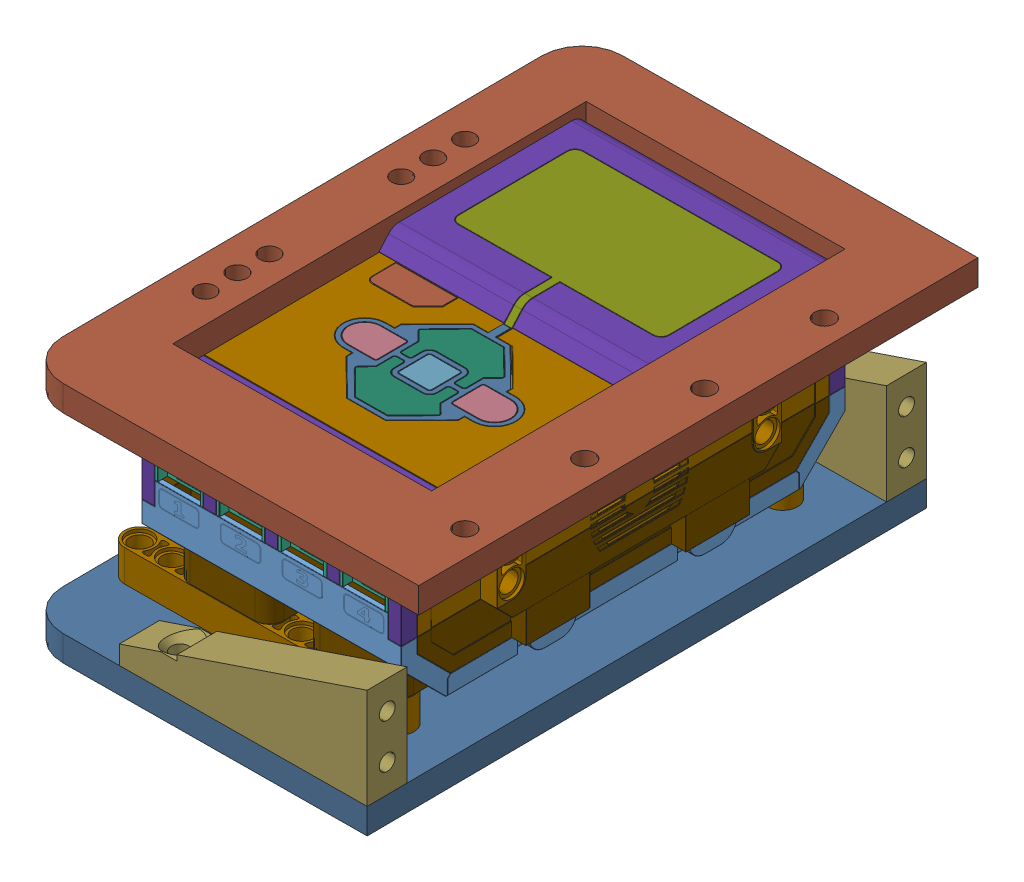
SolidWorks assembly EV3MountAssem, configuration Default. Lengths in mm.
Overall size (98.77 60.15 140.75).
51 component instances, 30 part files, 34 mates.
Components (placement in the parent):
- LEGOEV3BRAIN-1: LEGOEV3BRAIN [Default] at (-108.1242 39.401 63.9633) x (0.99997 0 -0.007691) z (0.007691 0 0.99997) size (72.13 50.8 111.2)
  - 95646c01.stp-1: 95646c01.stp [Default] at origin size (72.13 50.8 111.2)
    - 95656.stp-1: 95656.stp [Default] at (0 -35.2 -16) size (68.8 24 88.8)
      - 11142-LtBluishGray.stp-1: 11142-LtBluishGray.stp [Default] at origin size (68.8 20.8 88.8)
      - 11143-LtBluishGray.stp-1: 11143-LtBluishGray.stp [Default] at (-0.4 -0.4 0) size (50 15.2 87.61)
      - 56554-ElectricAlloy.stp-1: 56554-ElectricAlloy.stp [Default] at (-22.8 4.4 -36) x (0 1 0) z (0 0 1) size (5.6 5.52 5.6)
      - 56555-ElectricAlloy.stp-1: 56555-ElectricAlloy.stp [Default] at (-20.8 4.4 36.4) x (0 0 -1) z (-1 0 0) size (9.6 8.8 0.8)
      - 11177-TransGeen.stp-1: 11177-TransGeen.stp [Default] at (9.6 -8 41.6) x (1 0 0) z (0 -1 0) size (3.2 5.6 3.2)
      - 11177-TransRed.stp-1: 11177-TransRed.stp [Default] at (14.8 -8 41.6) x (1 0 0) z (0 -1 0) size (3.2 5.6 3.2)
      - 11186-Black.stp-1: 11186-Black.stp [Default] at (0 0.8 40) x (0 1 0) z (1 0 0) size (7.2 7.2 4.8)
      - u9208.stp-1: u9208.stp [Default] at (21.6 4.4 36.8) x (1 0 0) z (0 0 -1) size (3.2 8.8 3.2)
      - u9208.stp-2: u9208.stp [Default] at (21.6 4.4 -40) x (1 0 0) z (0 0 -1) size (3.2 8.8 3.2)
      - u9208.stp-3: u9208.stp [Default] at (21.6 4.4 0) x (1 0 0) z (0 0 -1) size (3.2 8.8 3.2)
      - u9208.stp-4: u9208.stp [Default] at (-20.8 4.4 28) x (1 0 0) z (0 0 -1) size (3.2 8.8 3.2)
      - u9208.stp-5: u9208.stp [Default] at (-20.8 4.4 -27.6) x (1 0 0) z (0 0 -1) size (3.2 8.8 3.2)
    - 99141p01-White.stp-1: 99141p01-White.stp [Default] at origin size (72.13 26.01 104.41)
    - 11026-TransClear.stp-1: 11026-TransClear.stp [Default] at (0 -2.6 0) size (42.56 5.2 35.4)
    - 11030-LtBluishGray.stp-1: 11030-LtBluishGray.stp [Default] at (-20 -2.5473 -15.88) size (15.28 5.2 7.44)
    - 11036-LCD.stp-1: 11036-LCD.stp [Default] at (0 1.999 -45.7343) size (52 1.6 40)
    - 99145-LtBluishGray.stp-1: 99145-LtBluishGray.stp [Default] at (-16 -2.6 0) size (10.88 5.2 8.16)
    - 99145-LtBluishGray.stp-2: 99145-LtBluishGray.stp [Default] at (16 -2.6 0) x (-1 0 0) z (0 0 -1) size (10.88 5.2 8.16)
    - 99146-LtBluishGray.stp-1: 99146-LtBluishGray.stp [Default] at (0 -2.6 0) size (8.16 5.2 8.16)
    - 99147-LtBluishGray.stp-1: 99147-LtBluishGray.stp [Default] at (0 -2.6 7.98) x (-1 0 0) z (0 0 -1) size (20.74 5.2 14)
    - 99147-LtBluishGray.stp-2: 99147-LtBluishGray.stp [Default] at (0 -2.6 -7.98) size (20.74 5.2 14)
    - 99148p01-TransClear.stp-1: 99148p01-TransClear.stp [Default] at (0 2.8 -47.2) size (52 8 43.2)
    - 99141s01-LtBluishGray.stp-1: 99141s01-LtBluishGray.stp [Default] at (0 0 2.2) size (64 27.2 111.2)
    - 11025-White.stp-1: 11025-White.stp [Default] at (0 -26.8 -16) size (71.6 22 103.2)
    - 11025s02-LtBluishGray.stp-1: 11025s02-LtBluishGray.stp [Default] at (0 -23.2 -16) size (64 22 111.2)
    - 11032-Black.stp-1: 11032-Black.stp [Default] at (-27.6 -14.6 -32) x (0 0 1) z (-1 0 0) size (14.4 6 14.4)
    - 11033-Black.stp-1: 11033-Black.stp [Default] at (23.2 -15.6 -68.8) x (-1 0 0) z (0 0 -1) size (8.2 4.2 10)
    - 11034-Black.stp-1: 11034-Black.stp [Default] at (-34.8 -16.6 -12) x (0 0 1) z (-1 0 0) size (14.4 2 15.2)
    - 11035-LtBluishGray.stp-1: 11035-LtBluishGray.stp [Default] at (-6 -10.8 -71.6) x (-1 0 0) z (0 0 -1) size (45.6 14.56 14.4)
    - 54732b-LtBluishGray.stp-1: 54732b-LtBluishGray.stp [Default] at (-22.8 -10.8 39.6) size (12 14.56 14.4)
    - 54732b-LtBluishGray.stp-2: 54732b-LtBluishGray.stp [Default] at (-7.6 -10.8 39.6) size (12 14.56 14.4)
    - 54732b-LtBluishGray.stp-3: 54732b-LtBluishGray.stp [Default] at (7.6 -10.8 39.6) size (12 14.56 14.4)
    - 54732b-LtBluishGray.stp-4: 54732b-LtBluishGray.stp [Default] at (22.8 -10.8 39.6) size (12 14.56 14.4)
    - 97622-PCB.stp-1: 97622-PCB.stp [Default] at (0 -6 0) size (48 1.6 40)
- 067_Pin-1: 067_Pin [Pin Without Friction Ridges Lengthwise] at (-115.8778 -0.199 96.0239) x (0 -1 0) z (0.00723 0 0.999974) size (15.6 5.8 5.8)
- 067_Pin-2: 067_Pin [Pin Without Friction Ridges Lengthwise] at (-84.6171 -0.199 -0.2194) x (0 -1 0) z (0.00662 0 0.999978) size (15.6 5.8 5.8)
- 067_Pin-3: 067_Pin [Pin Without Friction Ridges Lengthwise] at (-100.6166 -0.199 -0.0963) x (0 -1 0) z (-0.01457 0 0.999894) size (15.6 5.8 5.8)
- 067_Pin-4: 067_Pin [Pin Without Friction Ridges Lengthwise] at (-99.8783 -0.199 95.9009) x (0 1 0) z (0.010456 0 0.999945) size (15.6 5.8 5.8)
- 067_Pin-5: 067_Pin [Pin Without Friction Ridges Lengthwise] at (-83.8788 -0.199 95.7778) x (0 -1 0) z (0.00723 0 0.999974) size (15.6 5.8 5.8)
- 067_Pin-6: 067_Pin [Pin Without Friction Ridges Lengthwise] at (-131.8773 -0.199 96.147) x (0 -1 0) z (0.027134 0 0.999632) size (15.6 5.8 5.8)
- 067_Pin-7: 067_Pin [Pin Without Friction Ridges Lengthwise] at (-132.6157 -0.199 0.1498) x (0 -1 0) z (-0.015279 0 0.999883) size (15.6 5.8 5.8)
- 067_Pin-8: 067_Pin [Pin Without Friction Ridges Lengthwise] at (-116.6161 -0.199 0.0267) x (0 -1 0) z (0.00723 0 0.999974) size (15.6 5.8 5.8)
- 066_Lego_Technic_M_Beams-1: 066_Lego_Technic_M_Beams [L40490] at (-147.8769 -4.124 96.27) x (0.99997 0 -0.007691) z (0 -1 0) size (71.4 7.4 7.85)
- 066_Lego_Technic_M_Beams-2: 066_Lego_Technic_M_Beams [L40490] at (-148.6152 -4.124 0.2729) x (0.99997 0 -0.007691) z (0 -1 0) size (71.4 7.4 7.85)
- 069_EV3-6: 069_EV3 [Default] at (46.3426 -14.399 -58.7978) x (0.99997 0 -0.007691) z (0.007691 0 0.99997) size (85 6.35 140)
- 070_Top-1: 070_Top [Default] at (-110.5302 39.401 55.873) x (0.99997 0 -0.007691) z (0.007691 0 0.99997) size (97.7 6.35 140)
- 071_Support-1: 071_Support [Default] at (-112.3869 -8.049 107.9974) x (0.007691 0 0.99997) z (-0.99997 0 0.007691) size (10 25 61.12)
- 071_Support-2: 071_Support [Default] at (-113.3867 -8.049 -21.9987) x (0.007691 0 0.99997) z (-0.99997 0 0.007691) size (10 25 61.12)
Mates (geometry in assembly coordinates):
- Concentric1: concentric anti-aligned: cylinder of LEGOEV3BRAIN-1/95646c01.stp-1/11025-White.stp-1 through (-99.8783 -0.199 95.9009) axis (0 1 0) radius 2.4; cylinder of 067_Pin-4 through (-99.8783 -0.199 95.9009) axis (0 -1 0) radius 2.3
- Coincident2: coincident anti-aligned: plane of LEGOEV3BRAIN-1/95646c01.stp-1/11025-White.stp-1 through (-99.8783 0.601 95.9009) normal (0 -1 0); plane of 067_Pin-4 through (-102.7781 0.601 95.9312) normal (0 1 0)
- Concentric2: concentric anti-aligned: cylinder of LEGOEV3BRAIN-1/95646c01.stp-1/11025-White.stp-1 through (-115.8778 -0.199 96.0239) axis (0 -1 0) radius 2.4; cylinder of 067_Pin-1 through (-115.8778 -0.199 96.0239) axis (0 1 0) radius 2.3
- Coincident7: coincident anti-aligned: plane of LEGOEV3BRAIN-1/95646c01.stp-1/11025-White.stp-1 through (-115.8778 0.601 96.0239) normal (0 -1 0); plane of 067_Pin-1 through (-112.9779 0.601 96.0029) normal (0 1 0)
- Concentric3: concentric aligned: cylinder of LEGOEV3BRAIN-1/95646c01.stp-1/11025-White.stp-1 through (-131.8773 -0.199 96.147) axis (0 -1 0) radius 2.4; cylinder of 067_Pin-6 through (-131.8773 -0.199 96.147) axis (0 -1 0) radius 2.3
- Concentric4: concentric anti-aligned: cylinder of LEGOEV3BRAIN-1/95646c01.stp-1/11025-White.stp-1 through (-83.8788 -0.199 95.7778) axis (0 1 0) radius 2.4; cylinder of 067_Pin-5 through (-83.8788 -0.199 95.7778) axis (0 -1 0) radius 2.3
- Concentric5: concentric anti-aligned: cylinder of LEGOEV3BRAIN-1/95646c01.stp-1/11025-White.stp-1 through (-132.6157 -0.199 0.1498) axis (0 1 0) radius 2.4; cylinder of 067_Pin-7 through (-132.6157 -0.199 0.1498) axis (0 -1 0) radius 2.3
- Concentric6: concentric anti-aligned: cylinder of LEGOEV3BRAIN-1/95646c01.stp-1/11025-White.stp-1 through (-116.6161 -0.199 0.0267) axis (0 1 0) radius 2.4; cylinder of 067_Pin-8 through (-116.6161 -0.199 0.0267) axis (0 -1 0) radius 2.3
- Concentric7: concentric anti-aligned: cylinder of LEGOEV3BRAIN-1/95646c01.stp-1/11025-White.stp-1 through (-100.6166 -0.199 -0.0963) axis (0 -1 0) radius 2.4; cylinder of 067_Pin-3 through (-100.6166 -0.199 -0.0963) axis (0 1 0) radius 2.3
- Concentric8: concentric anti-aligned: cylinder of LEGOEV3BRAIN-1/95646c01.stp-1/11025-White.stp-1 through (-84.6171 -0.199 -0.2194) axis (0 -1 0) radius 2.4; cylinder of 067_Pin-2 through (-84.6171 -0.199 -0.2194) axis (0 1 0) radius 2.3
- Coincident8: coincident anti-aligned: plane of LEGOEV3BRAIN-1/95646c01.stp-1/11025-White.stp-1 through (-84.617 0.601 -0.2194) normal (0 -1 0); plane of 067_Pin-2 through (-81.7171 0.601 -0.2386) normal (0 1 0)
- Coincident9: coincident anti-aligned: plane of LEGOEV3BRAIN-1/95646c01.stp-1/11025-White.stp-1 through (-100.6166 0.601 -0.0963) normal (0 -1 0); plane of 067_Pin-3 through (-97.7169 0.601 -0.0541) normal (0 1 0)
- Coincident10: coincident anti-aligned: plane of LEGOEV3BRAIN-1/95646c01.stp-1/11025-White.stp-1 through (-131.8775 0.601 96.147) normal (0 -1 0); plane of 067_Pin-6 through (-128.9784 0.601 96.0683) normal (0 1 0)
- Coincident11: coincident anti-aligned: plane of LEGOEV3BRAIN-1/95646c01.stp-1/11025-White.stp-1 through (-132.6158 0.601 0.1498) normal (0 -1 0); plane of 067_Pin-7 through (-129.716 0.601 0.1941) normal (0 1 0)
- Coincident12: coincident anti-aligned: plane of LEGOEV3BRAIN-1/95646c01.stp-1/11025-White.stp-1 through (-116.6161 0.601 0.0267) normal (0 -1 0); plane of 067_Pin-8 through (-113.7162 0.601 0.0058) normal (0 1 0)
- Concentric10: concentric aligned: cylinder of 067_Pin-2 through (-84.6171 -0.199 -0.2194) axis (0 1 0) radius 2.3; cylinder of 066_Lego_Technic_M_Beams-2 through (-84.6171 -1.699 -0.2194) axis (0 1 0) radius 2.425
- Concentric11: concentric aligned: cylinder of 067_Pin-7 through (-132.6157 -0.199 0.1498) axis (0 1 0) radius 2.3; cylinder of 066_Lego_Technic_M_Beams-2 through (-132.6157 -1.699 0.1498) axis (0 1 0) radius 2.425
- Concentric12: concentric aligned: cylinder of 067_Pin-5 through (-83.8788 -0.199 95.7778) axis (0 1 0) radius 2.3; cylinder of 066_Lego_Technic_M_Beams-1 through (-83.8788 -1.699 95.7778) axis (0 1 0) radius 2.425
- Concentric13: concentric aligned: cylinder of 067_Pin-6 through (-131.8773 -0.199 96.147) axis (0 1 0) radius 2.3; cylinder of 066_Lego_Technic_M_Beams-1 through (-131.8773 -1.699 96.147) axis (0 1 0) radius 2.425
- Coincident16: coincident anti-aligned: plane of LEGOEV3BRAIN-1/95646c01.stp-1/11025-White.stp-1 through (-83.8786 0.601 95.7778) normal (0 -1 0); plane of 067_Pin-5 through (-80.9788 0.601 95.7568) normal (0 1 0)
- Coincident17: coincident anti-aligned: plane of 067_Pin-1 through (-112.9779 -0.999 96.0029) normal (0 -1 0); plane of 066_Lego_Technic_M_Beams-1 through (-134.3023 -0.999 96.1656) normal (0 1 0)
- Coincident18: coincident anti-aligned: plane of 067_Pin-3 through (-97.7169 -0.999 -0.0541) normal (0 -1 0); plane of 066_Lego_Technic_M_Beams-2 through (-103.0415 -0.999 -0.0777) normal (0 1 0)
- Coincident19: coincident anti-aligned: plane of 066_Lego_Technic_M_Beams-2 through (-152.3151 -8.049 0.3013) normal (0 -1 0); plane of 069_EV3-6 through (46.3426 -8.049 -58.7978) normal (0 1 0)
- Distance1: distance = 2 mm aligned: plane of 069_EV3-6 through (-70.9867 -8.049 -22.3248) normal (0.99997 0 -0.007691); plane of LEGOEV3BRAIN-1/95646c01.stp-1/99141p01-White.stp-1 through (-72.3887 22.1608 55.4386) normal (0.99997 0 -0.007691)
- Coincident22: coincident aligned: plane of 069_EV3-6 through (-155.9842 -8.049 -21.6711) normal (-0.99997 0 0.007691); plane of 070_Top-1 through (-155.9842 45.751 -21.6711) normal (-0.99997 0 0.007691)
- Coincident23: coincident aligned: plane of 069_EV3-6 through (-155.9842 -8.049 -21.6711) normal (-0.007691 0 -0.99997); plane of 070_Top-1 through (-155.9842 45.751 -21.6711) normal (-0.007691 0 -0.99997)
- Coincident26: coincident anti-aligned: plane of LEGOEV3BRAIN-1/95646c01.stp-1/99141p01-White.stp-1 through (-108.1181 39.401 64.7529) normal (0 1 0); plane of 070_Top-1 through (-110.5302 39.401 55.873) normal (0 -1 0)
- Distance4: distance = 14.4 mm aligned: plane of 069_EV3-6 through (-154.9075 -8.049 118.3247) normal (0.007691 0 0.99997); plane of LEGOEV3BRAIN-1/95646c01.stp-1/99141s01-LtBluishGray.stp-1 through (-107.8196 36.361 103.5622) normal (0.007691 0 0.99997)
- Coincident27: coincident anti-aligned: plane of 069_EV3-6 through (46.3426 -8.049 -58.7978) normal (0 1 0); plane of 071_Support-1 through (-69.91 -8.049 117.671) normal (0 -1 0)
- Coincident28: coincident aligned: plane of 069_EV3-6 through (-154.9075 -8.049 118.3247) normal (0.007691 0 0.99997); plane of 071_Support-1 through (-112.31 -8.049 117.9971) normal (0.007691 0 0.99997)
- Coincident29: coincident aligned: plane of 069_EV3-6 through (-70.9867 -8.049 -22.3248) normal (0.99997 0 -0.007691); plane of 071_Support-1 through (-69.91 16.951 117.671) normal (0.99997 0 -0.007691)
- Coincident30: coincident aligned: plane of 069_EV3-6 through (-155.9842 -8.049 -21.6711) normal (-0.007691 0 -0.99997); plane of 071_Support-2 through (-113.3867 -8.049 -21.9987) normal (-0.007691 0 -0.99997)
- Coincident31: coincident: line of 069_EV3-6 through (-69.91 -8.049 117.671) axis (-0.007691 0 -0.99997); plane of 071_Support-2 through (-70.9098 -8.049 -12.3251) normal (0 -1 0)
- Coincident32: coincident aligned: plane of 069_EV3-6 through (-70.9867 -8.049 -22.3248) normal (0.99997 0 -0.007691); plane of 071_Support-2 through (-70.9098 16.951 -12.3251) normal (0.99997 0 -0.007691)
